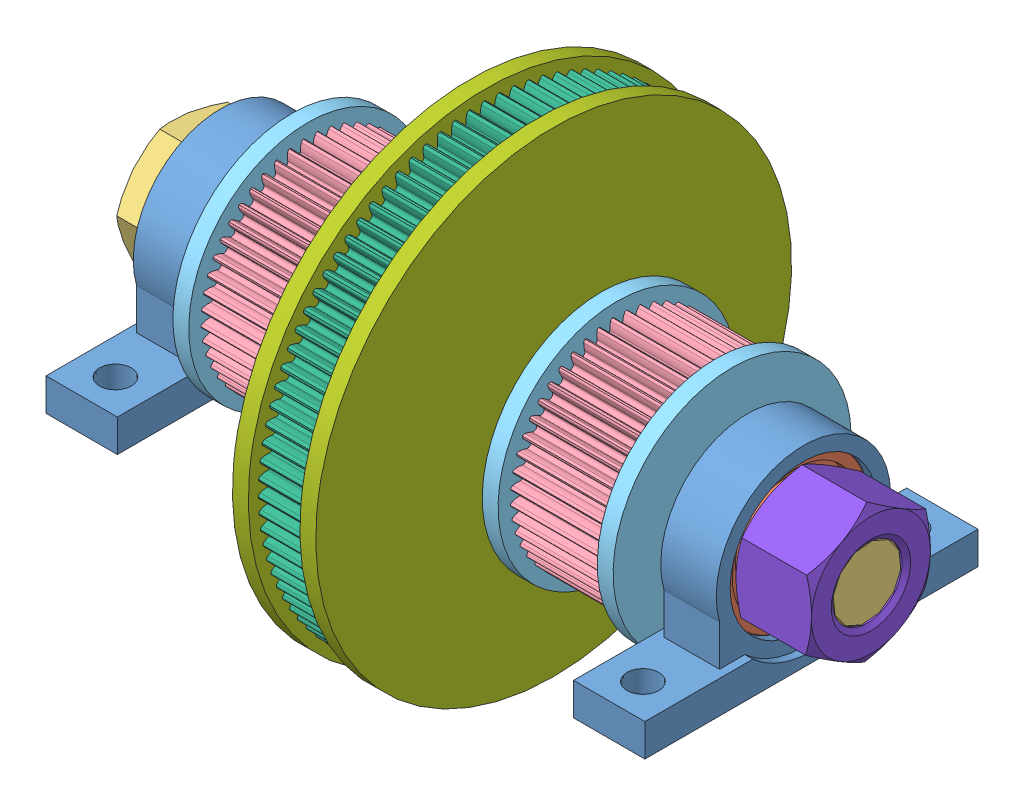
SolidWorks assembly EnsambleDePoleas, configuration Default. Lengths in mm.
Overall size (174.4 137.01 137.01).
17 component instances, 8 part files, 34 mates.
Components (placement in the parent):
- Ensamblaje 8M drive assy-1: Ensamblaje 8M drive assy [Predeterminado] at (-109.3931 78.4683 55.8199) x (0 0 -1) z (1 0 0) size (84 46.5 18)
  - fijadores del eje-1: fijadores del eje [Predeterminado] at (36.2208 -24.0928 75) size (84 46.5 18)
  - radial ball bearing_68_skf-3: radial ball bearing_68_skf [SKF - 61904 - 14,SI,NC,14_68] at (-5.7792 0.4072 84.5) x (0 0 1) z (0.143935 -0.989587 0) size (9 37 37)
- hex screw gradec_din-1: hex screw gradec_din [DIN EN 24018 - M20 x 180-WN] at (-42.7931 78.8755 61.5992) x (1 0 0) z (0 -0.988123 0.153664) size (173.4 34.64 30)
- Polea60-1: Polea60 [Default] at (67.6069 78.8755 61.5992) x (0 -0.988123 0.153664) z (0 0.153664 0.988123) size (53.81 25 53.81)
- Protector60-1: Protector60 [Default] at (18.6069 78.8755 61.5992) x (0 0.988123 -0.153664) z (0 0.153664 0.988123) size (60 4 60)
- Polea120-1: Polea120 [Default] at (34.6069 78.8755 61.5992) x (0 -0.988123 0.153664) z (0 0.153664 0.988123) size (114.93 13 114.93)
- Protector120-1: Protector120 [Default] at (51.6069 78.8755 61.5992) x (0 0.988123 -0.153664) z (0 0.153664 0.988123) size (120 4 120)
- Protector120-2: Protector120 [Default] at (34.6069 78.8755 61.5992) x (0 0.988123 -0.153664) z (0 0.153664 0.988123) size (120 4 120)
- Polea60-8: Polea60 [Default] at (14.6069 78.8755 61.5992) x (0 -0.988123 0.153664) z (0 -0.153664 -0.988123) size (53.81 25 53.81)
- Protector60-7: Protector60 [Default] at (-14.3931 78.8755 61.5992) x (0 0.988123 -0.153664) z (0 -0.153664 -0.988123) size (60 4 60)
- Ensamblaje 8M drive assy-3: Ensamblaje 8M drive assy [Predeterminado] at (23.6069 78.4683 55.8199) x (0 0 -1) z (1 0 0) size (84 46.5 18)
  - fijadores del eje-1: fijadores del eje [Predeterminado] at (36.2208 -24.0928 75) size (84 46.5 18)
  - radial ball bearing_68_skf-3: radial ball bearing_68_skf [SKF - 61904 - 14,SI,NC,14_68] at (-5.7792 0.4072 84.5) x (0 0 1) z (0.143935 -0.989587 0) size (9 37 37)
- hex nut gradec_din-1: hex nut gradec_din [Hexagon Nut ISO 4034 - M20 - N] at (131.6069 78.8755 61.5992) x (0 -0.874192 -0.48558) z (1 0 0) size (30 34.64 19)
- Protector60-8: Protector60 [Default] at (63.6069 78.8755 61.5992) x (0 0.988123 -0.153664) z (0 -0.153664 -0.988123) size (60 4 60)
- Protector60-10: Protector60 [Default] at (96.6069 78.8755 61.5992) x (0 -0.988123 0.153664) z (0 -0.153664 -0.988123) size (60 4 60)
Mates (geometry in assembly coordinates):
- Concéntrica1: concentric: cylinder of Ensamblaje 8M drive assy-1/radial ball bearing_68_skf-3 through (-45.5306 78.8755 61.5992) axis (1 0 0) radius 10; cylinder of Ensamblaje 8M drive assy-3/radial ball bearing_68_skf-3 through (87.4694 78.8755 61.5992) axis (1 0 0) radius 10
- Paralelo1: parallel: line of Ensamblaje 8M drive assy-1/fijadores del eje-1 through (-16.3931 54.3755 103.5992) axis (0 0 -1); line of Ensamblaje 8M drive assy-3/fijadores del eje-1 through (98.6069 54.3755 103.5992) axis (0 0 -1)
- Distancia1: distance = 115 mm: plane of Ensamblaje 8M drive assy-3/fijadores del eje-1 through (98.6069 78.8755 61.5992) normal (-1 0 0); plane of Ensamblaje 8M drive assy-1/fijadores del eje-1 through (-16.3931 78.8755 61.5992) normal (1 0 0)
- Concéntrica3: concentric: cylinder of Polea60-8 through (-10.3931 78.8755 61.5992) axis (1 0 0) radius 10; cylinder of Protector60-7 through (-20.3931 78.8755 61.5992) axis (1 0 0) radius 10
- Concéntrica4: concentric: cylinder of Protector60-1 through (24.6069 78.8755 61.5992) axis (-1 0 0) radius 10; cylinder of Polea60-8 through (-10.3931 78.8755 61.5992) axis (1 0 0) radius 10
- Paralelo2: parallel: line of Protector60-7 through (-10.3931 78.8755 61.5992) axis (0 0.153664 0.988123); line of Protector60-1 through (14.6069 78.8755 61.5992) axis (0 -0.153664 -0.988123)
- Paralelo3: parallel: line of Protector60-7 through (-10.3931 78.8755 61.5992) axis (0 0.153664 0.988123); line of Polea60-8 through (14.6069 78.8755 61.5992) axis (0 -0.153664 -0.988123)
- Coincidente8: coincident: plane of Polea60-8 through (-10.3931 78.8755 61.5992) normal (-1 0 0); plane of Protector60-7 through (-10.3931 78.8755 61.5992) normal (1 0 0)
- Coincidente9: coincident: plane of Protector60-1 through (14.6069 78.8755 61.5992) normal (-1 0 0); plane of Polea60-8 through (14.6069 78.8755 61.5992) normal (1 0 0)
- Distancia2: distance = 2 mm: plane of Ensamblaje 8M drive assy-1/fijadores del eje-1 through (-16.3931 78.8755 61.5992) normal (1 0 0); plane of Protector60-7 through (-14.3931 78.8755 61.5992) normal (-1 0 0)
- Coincidente16: coincident: plane of Polea60-1 through (92.6069 78.8755 61.5992) normal (1 0 0); plane of Protector60-10 through (92.6069 78.8755 61.5992) normal (-1 0 0)
- Concéntrica9: concentric: cylinder of Polea60-1 through (92.6069 78.8755 61.5992) axis (-1 0 0) radius 10; cylinder of Protector60-10 through (102.6069 78.8755 61.5992) axis (-1 0 0) radius 10
- Coincidente17: coincident: plane of Polea60-1 through (67.6069 78.8755 61.5992) normal (-1 0 0); plane of Protector60-8 through (67.6069 78.8755 61.5992) normal (1 0 0)
- Concéntrica10: concentric: cylinder of Polea60-1 through (92.6069 78.8755 61.5992) axis (-1 0 0) radius 10; cylinder of Protector60-8 through (57.6069 78.8755 61.5992) axis (1 0 0) radius 10
- Paralelo7: parallel: line of Polea60-1 through (67.6069 78.8755 61.5992) axis (0 0.153664 0.988123); line of Protector60-8 through (67.6069 78.8755 61.5992) axis (0 0.153664 0.988123)
- Paralelo8: parallel: line of Protector60-8 through (67.6069 78.8755 61.5992) axis (0 0.153664 0.988123); line of Protector60-10 through (92.6069 78.8755 61.5992) axis (0 0.153664 0.988123)
- Coincidente22: coincident: plane of Ensamblaje 8M drive assy-1/radial ball bearing_68_skf-3 through (-29.3931 77.0691 74.0185) normal (-1 0 0); plane of hex screw gradec_din-1 through (-29.3931 81.537 78.714) normal (1 0 0)
- Concéntrica14: concentric: cylinder of Ensamblaje 8M drive assy-1/radial ball bearing_68_skf-3 through (-45.5306 78.8755 61.5992) axis (1 0 0) radius 10; cylinder of hex screw gradec_din-1 through (-42.7931 78.8755 61.5992) axis (-1 0 0) radius 10
- Concéntrica15: concentric: cylinder of hex screw gradec_din-1 through (-42.7931 78.8755 61.5992) axis (-1 0 0) radius 10; cylinder of Polea60-8 through (-10.3931 78.8755 61.5992) axis (1 0 0) radius 10
- Paralelo11: parallel: line of hex screw gradec_din-1 through (-42.7931 81.537 78.714) axis (0 -0.153664 -0.988123); line of Protector60-7 through (-10.3931 78.8755 61.5992) axis (0 0.153664 0.988123)
- Concéntrica17: concentric: cylinder of hex screw gradec_din-1 through (-42.7931 78.8755 61.5992) axis (-1 0 0) radius 10; cylinder of Polea60-1 through (92.6069 78.8755 61.5992) axis (-1 0 0) radius 10
- Distancia4: distance = 2 mm: plane of Protector60-10 through (96.6069 78.8755 61.5992) normal (1 0 0); plane of Ensamblaje 8M drive assy-3/fijadores del eje-1 through (98.6069 78.8755 61.5992) normal (-1 0 0)
- Paralelo12: parallel: line of hex screw gradec_din-1 through (-42.7931 81.537 78.714) axis (0 -0.153664 -0.988123); line of Protector60-8 through (67.6069 78.8755 61.5992) axis (0 0.153664 0.988123)
- Concéntrica18: concentric: cylinder of Polea120-1 through (47.6069 78.8755 61.5992) axis (-1 0 0) radius 10; cylinder of Protector120-1 through (57.6069 78.8755 61.5992) axis (-1 0 0) radius 10
- Coincidente25: coincident: plane of Polea120-1 through (47.6069 78.8755 61.5992) normal (1 0 0); plane of Protector120-1 through (47.6069 78.8755 61.5992) normal (-1 0 0)
- Coincidente26: coincident: plane of Polea120-1 through (34.6069 78.8755 61.5992) normal (-1 0 0); plane of Protector120-2 through (34.6069 78.8755 61.5992) normal (1 0 0)
- Concéntrica19: concentric: cylinder of Polea120-1 through (47.6069 78.8755 61.5992) axis (-1 0 0) radius 10; cylinder of Protector120-2 through (40.6069 78.8755 61.5992) axis (-1 0 0) radius 10
- Paralelo13: parallel: line of Polea120-1 through (34.6069 78.8755 61.5992) axis (0 0.153664 0.988123); line of Protector120-2 through (30.6069 78.8755 61.5992) axis (0 -0.153664 -0.988123)
- Paralelo14: parallel: line of Protector120-1 through (47.6069 78.8755 61.5992) axis (0 -0.153664 -0.988123); line of Protector120-2 through (30.6069 78.8755 61.5992) axis (0 -0.153664 -0.988123)
- Concéntrica20: concentric: cylinder of hex screw gradec_din-1 through (-42.7931 78.8755 61.5992) axis (-1 0 0) radius 10; cylinder of Polea120-1 through (47.6069 78.8755 61.5992) axis (-1 0 0) radius 10
- Distancia6: distance = 47 mm: plane of Protector120-1 through (51.6069 78.8755 61.5992) normal (1 0 0); plane of Ensamblaje 8M drive assy-3/fijadores del eje-1 through (98.6069 78.8755 61.5992) normal (-1 0 0)
- Paralelo15: parallel: line of hex screw gradec_din-1 through (-42.7931 81.537 78.714) axis (0 -0.153664 -0.988123); line of Protector120-2 through (30.6069 78.8755 61.5992) axis (0 -0.153664 -0.988123)
- Concéntrica21: concentric: cylinder of hex screw gradec_din-1 through (-42.7931 78.8755 61.5992) axis (-1 0 0) radius 10; cylinder of hex nut gradec_din-1 through (112.6069 78.8755 61.5992) axis (1 0 0) radius 8.75
- Coincidente33: coincident: plane of Ensamblaje 8M drive assy-3/radial ball bearing_68_skf-3 through (112.6069 77.393 71.7919) normal (1 0 0); plane of hex nut gradec_din-1 through (112.6069 87.286 46.4577) normal (-1 0 0)
